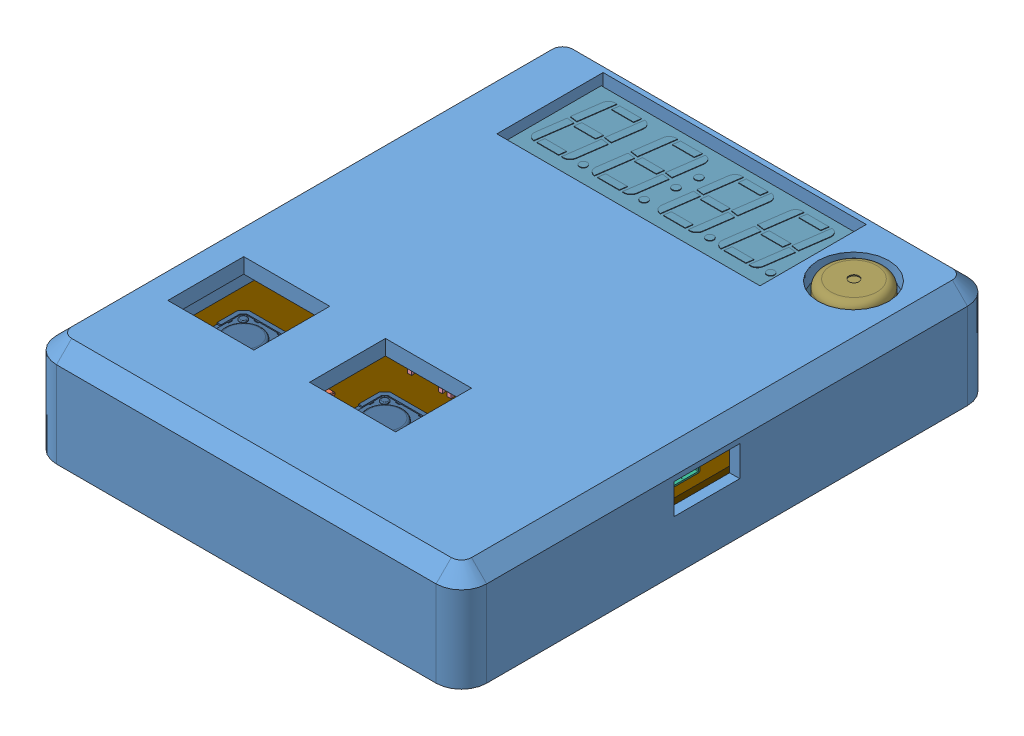
SolidWorks assembly Timer_AssemV1, configuration Default. Lengths in mm.
Overall size (85 20.23 105).
98 component instances, 19 part files, 4 mates.
Components (placement in the parent):
- Timer_EncloserV1-1: Timer_EncloserV1 [Default] at (21.1772 85.8969 138.7154) size (85 17 105)
- DANYS_Kitchen_TimerV3.step-1: DANYS_Kitchen_TimerV3.step [Default] at (-125.543 94.9469 34.9235) x (1 0 0) z (0 1 0) size (78.74 99.06 18.23)
  - R_0805_2012Metric.step-1: R_0805_2012Metric.step [Default] at (146.1142 -79.1758 1.65) x (0 1 0) z (0 0 1) size (2 1.2 0.45)
    - SOLID.step-1: SOLID.step [Default] at origin size (2 1.2 0.45)
  - R_0603_1608Metric.step-1: R_0603_1608Metric.step [Default] at (127 -96.52 1.65) x (0 1 0) z (0 0 1) size (1.6 0.8 0.45)
    - SOLID-0.step-1: SOLID-0.step [Default] at origin size (1.6 0.8 0.45)
  - R_0805_2012Metric.step-2: R_0805_2012Metric.step [Default] at (134.6842 -79.1758 1.65) x (0 1 0) z (0 0 1) size (2 1.2 0.45)
    - SOLID.step-1: SOLID.step [Default] at origin size (2 1.2 0.45)
  - C_0603_1608Metric.step-1: C_0603_1608Metric.step [Default] at (111.635 -90.2 1.65) size (1.6 0.8 0.8)
    - SOLID-1.step-1: SOLID-1.step [Default] at origin size (1.6 0.8 0.8)
  - LED_0805_2012Metric.step-1: LED_0805_2012Metric.step [Default] at (160.845 -95.0025 1.65) x (0 -1 0) z (0 0 1) size (2 1.25 1.1)
    - SOLID-2.step-1: SOLID-2.step [Default] at origin size (2 1.25 1.1)
  - USB_Mini-B_Lumberg_2486_01_Horizontal.step-1: USB_Mini-B_Lumberg_2486_01_Horizontal.step [Default] at (179.07 -107.95 1.65) x (0 1 0) z (0 0 1) size (9.9 9.21 5)
    - SOLID-3.step-1: SOLID-3.step [Default] at origin size (9.9 9.21 5)
  - R_0805_2012Metric.step-3: R_0805_2012Metric.step [Default] at (138.4942 -79.1758 1.65) x (0 1 0) z (0 0 1) size (2 1.2 0.45)
    - SOLID.step-1: SOLID.step [Default] at origin size (2 1.2 0.45)
  - C_0603_1608Metric.step-2: C_0603_1608Metric.step [Default] at (144.0856 -95.1424 1.65) x (0 1 0) z (0 0 1) size (1.6 0.8 0.8)
    - SOLID-1.step-1: SOLID-1.step [Default] at origin size (1.6 0.8 0.8)
  - LED_0805_2012Metric.step-2: LED_0805_2012Metric.step [Default] at (113.03 -63.8325 1.65) x (0 -1 0) z (0 0 1) size (2 1.25 1.1)
    - SOLID-2.step-1: SOLID-2.step [Default] at origin size (2 1.25 1.1)
  - R_0805_2012Metric.step-4: R_0805_2012Metric.step [Default] at (110.49 -68.58 1.65) x (0 1 0) z (0 0 1) size (2 1.2 0.45)
    - SOLID.step-1: SOLID.step [Default] at origin size (2 1.2 0.45)
  - R_0805_2012Metric.step-5: R_0805_2012Metric.step [Default] at (142.3042 -79.1758 1.65) x (0 1 0) z (0 0 1) size (2 1.2 0.45)
    - SOLID.step-1: SOLID.step [Default] at origin size (2 1.2 0.45)
  - R_0603_1608Metric.step-2: R_0603_1608Metric.step [Default] at (149.2111 -95.8706 1.65) size (1.6 0.8 0.45)
    - SOLID-0.step-1: SOLID-0.step [Default] at origin size (1.6 0.8 0.45)
  - C_0603_1608Metric.step-3: C_0603_1608Metric.step [Default] at (140.4888 -95.1249 1.65) x (0 -1 0) z (0 0 1) size (1.6 0.8 0.8)
    - SOLID-1.step-1: SOLID-1.step [Default] at origin size (1.6 0.8 0.8)
  - Crystal_SMD_Abracon_ABM8G-4Pin_3.2x2.5mm.step-1: Crystal_SMD_Abracon_ABM8G-4Pin_3.2x2.5mm.step [Default] at (136.5905 -94.9415 1.65) x (-1 0 0) z (0 0 1) size (3.2 2.5 0.64)
    - SOLID-4.step-1: SOLID-4.step [Default] at origin size (3.2 2.5 0.64)
  - C_0603_1608Metric.step-4: C_0603_1608Metric.step [Default] at (145.6251 -116.0418 1.65) x (0 -1 0) z (0 0 1) size (1.6 0.8 0.8)
    - SOLID-1.step-1: SOLID-1.step [Default] at origin size (1.6 0.8 0.8)
  - R_0805_2012Metric.step-6: R_0805_2012Metric.step [Default] at (134.62 -128.27 1.65) size (2 1.2 0.45)
    - SOLID.step-1: SOLID.step [Default] at origin size (2 1.2 0.45)
  - TSSOP-16_4.4x5mm_P0.65mm.step-1: TSSOP-16_4.4x5mm_P0.65mm.step [Default] at (134.8073 -86.6676 1.65) x (0 -1 0) z (0 0 1) size (6.4 5 1.1)
    - SOLID-5.step-1: SOLID-5.step [Default] at origin size (6.4 5 1.1)
  - C_0603_1608Metric.step-5: C_0603_1608Metric.step [Default] at (115.725 -93.98 1.65) x (-1 0 0) z (0 0 1) size (1.6 0.8 0.8)
    - SOLID-1.step-1: SOLID-1.step [Default] at origin size (1.6 0.8 0.8)
  - C_0603_1608Metric.step-6: C_0603_1608Metric.step [Default] at (152.6468 -106.8933 1.65) size (1.6 0.8 0.8)
    - SOLID-1.step-1: SOLID-1.step [Default] at origin size (1.6 0.8 0.8)
  - LED_0805_2012Metric.step-3: LED_0805_2012Metric.step [Default] at (110.49 -63.8325 1.65) x (0 -1 0) z (0 0 1) size (2 1.25 1.1)
    - SOLID-2.step-1: SOLID-2.step [Default] at origin size (2 1.25 1.1)
  - R_0603_1608Metric.step-3: R_0603_1608Metric.step [Default] at (164.1964 -95.2027 1.65) x (0 -1 0) z (0 0 1) size (1.6 0.8 0.45)
    - SOLID-0.step-1: SOLID-0.step [Default] at origin size (1.6 0.8 0.45)
  - C_0603_1608Metric.step-7: C_0603_1608Metric.step [Default] at (152.6692 -110.0092 1.65) size (1.6 0.8 0.8)
    - SOLID-1.step-1: SOLID-1.step [Default] at origin size (1.6 0.8 0.8)
  - R_0603_1608Metric.step-4: R_0603_1608Metric.step [Default] at (170.625 -107.1515 1.65) x (-1 0 0) z (0 0 1) size (1.6 0.8 0.45)
    - SOLID-0.step-1: SOLID-0.step [Default] at origin size (1.6 0.8 0.45)
  - TQFP-44_10x10mm_P0.8mm.step-1: TQFP-44_10x10mm_P0.8mm.step [Default] at (143.185 -106.68 1.65) x (-1 0 0) z (0 0 1) size (12 12 1.1)
    - SOLID-6.step-1: SOLID-6.step [Default] at origin size (12 12 1.1)
  - C_0603_1608Metric.step-8: C_0603_1608Metric.step [Default] at (111.635 -92.71 1.65) size (1.6 0.8 0.8)
    - SOLID-1.step-1: SOLID-1.step [Default] at origin size (1.6 0.8 0.8)
  - PTS125_SMD_Button.step-1: PTS125_SMD_Button.step [Default] at (120.65 -130.81 1.65) x (0 -1 0) z (-1 0 0) size (12 4.3 15.3)
    - SOLID-8.step-1: SOLID-8.step [Default] at origin size (12 4.3 15.3)
  - C_0603_1608Metric.step-9: C_0603_1608Metric.step [Default] at (138.43 -87.135 1.65) x (0 1 0) z (0 0 1) size (1.6 0.8 0.8)
    - SOLID-1.step-1: SOLID-1.step [Default] at origin size (1.6 0.8 0.8)
  - PinSocket_2x04_P2.54mm_Vertical.step-1: PinSocket_2x04_P2.54mm_Vertical.step [Default] at (123.86 -90.17 1.65) size (5.08 10.16 10.1)
    - SOLID-9.step-1: SOLID-9.step [Default] at origin size (5.08 10.16 10.1)
  - C_0603_1608Metric.step-10: C_0603_1608Metric.step [Default] at (152.6324 -105.2577 1.65) size (1.6 0.8 0.8)
    - SOLID-1.step-1: SOLID-1.step [Default] at origin size (1.6 0.8 0.8)
  - R_0805_2012Metric.step-7: R_0805_2012Metric.step [Default] at (119.4442 -79.1758 1.65) x (0 1 0) z (0 0 1) size (2 1.2 0.45)
    - SOLID.step-1: SOLID.step [Default] at origin size (2 1.2 0.45)
  - Buzzer_12x9.5RM7.6.step-1: Buzzer_12x9.5RM7.6.step [Default] at (172.73 -66.04 1.65) size (12 12 12.53)
    - SOLID-10.step-1: SOLID-10.step [Default] at origin size (12 12 12.53)
  - R_0805_2012Metric.step-8: R_0805_2012Metric.step [Default] at (123.2542 -79.1758 1.65) x (0 1 0) z (0 0 1) size (2 1.2 0.45)
    - SOLID.step-1: SOLID.step [Default] at origin size (2 1.2 0.45)
  - R_0805_2012Metric.step-9: R_0805_2012Metric.step [Default] at (134.62 -133.35 1.65) x (-1 0 0) z (0 0 1) size (2 1.2 0.45)
    - SOLID.step-1: SOLID.step [Default] at origin size (2 1.2 0.45)
  - C_0805_2012Metric.step-1: C_0805_2012Metric.step [Default] at (146.05 -94.93 1.65) x (0 1 0) z (0 0 1) size (2 1.25 1.25)
    - SOLID-11.step-1: SOLID-11.step [Default] at origin size (2 1.25 1.25)
  - CA56-12EWA.step-1: CA56-12EWA.step [Default] at (135.89 -73.66 1.65) x (0 1 0) z (0 0 1) size (19 50.3 12.2)
    - SOLID-12.step-1: SOLID-12.step [Default] at origin size (19 50.3 12.2)
  - SOT-23-6.step-1: SOT-23-6.step [Default] at (163.6975 -107.63 1.65) x (-1 0 0) z (0 0 1) size (2.8 2.9 1.55)
    - SOLID-13.step-1: SOLID-13.step [Default] at origin size (2.8 2.9 1.55)
  - C_0603_1608Metric.step-11: C_0603_1608Metric.step [Default] at (142.3246 -95.1338 1.65) x (0 1 0) z (0 0 1) size (1.6 0.8 0.8)
    - SOLID-1.step-1: SOLID-1.step [Default] at origin size (1.6 0.8 0.8)
  - C_0603_1608Metric.step-12: C_0603_1608Metric.step [Default] at (133.1636 -103.1567 1.65) x (-1 0 0) z (0 0 1) size (1.6 0.8 0.8)
    - SOLID-1.step-1: SOLID-1.step [Default] at origin size (1.6 0.8 0.8)
  - SOT-23-5.step-1: SOT-23-5.step [Default] at (116.215 -91.17 1.65) size (2.8 2.9 1.55)
    - SOLID-14.step-1: SOLID-14.step [Default] at origin size (2.8 2.9 1.55)
  - R_0805_2012Metric.step-10: R_0805_2012Metric.step [Default] at (127.0642 -79.1758 1.65) x (0 1 0) z (0 0 1) size (2 1.2 0.45)
    - SOLID.step-1: SOLID.step [Default] at origin size (2 1.2 0.45)
  - C_0603_1608Metric.step-13: C_0603_1608Metric.step [Default] at (147.3397 -116.0305 1.65) x (0 -1 0) z (0 0 1) size (1.6 0.8 0.8)
    - SOLID-1.step-1: SOLID-1.step [Default] at origin size (1.6 0.8 0.8)
  - R_0805_2012Metric.step-11: R_0805_2012Metric.step [Default] at (130.8742 -79.1758 1.65) x (0 1 0) z (0 0 1) size (2 1.2 0.45)
    - SOLID.step-1: SOLID.step [Default] at origin size (2 1.2 0.45)
  - R_0603_1608Metric.step-5: R_0603_1608Metric.step [Default] at (170.6603 -109.0096 1.65) x (-1 0 0) z (0 0 1) size (1.6 0.8 0.45)
    - SOLID-0.step-1: SOLID-0.step [Default] at origin size (1.6 0.8 0.45)
  - C_0603_1608Metric.step-14: C_0603_1608Metric.step [Default] at (139.4571 -115.9516 1.65) x (0 -1 0) z (0 0 1) size (1.6 0.8 0.8)
    - SOLID-1.step-1: SOLID-1.step [Default] at origin size (1.6 0.8 0.8)
  - R_0805_2012Metric.step-12: R_0805_2012Metric.step [Default] at (113.03 -68.58 1.65) x (0 1 0) z (0 0 1) size (2 1.2 0.45)
    - SOLID.step-1: SOLID.step [Default] at origin size (2 1.2 0.45)
  - PTS125_SMD_Button.step-2: PTS125_SMD_Button.step [Default] at (148.59 -130.81 1.65) x (0 1 0) z (1 0 0) size (12 4.3 15.3)
    - SOLID-8.step-1: SOLID-8.step [Default] at origin size (12 4.3 15.3)
  - PinSocket_2x03_P2.54mm_Vertical.step-1: PinSocket_2x03_P2.54mm_Vertical.step [Default] at (165.1 -100.33 -0.05) x (0 1 0) z (0 0 -1) size (5.08 7.62 10.1)
    - SOLID-7.step-1: SOLID-7.step [Default] at origin size (5.08 7.62 10.1)
  - PCB.step-1: PCB.step [Default] at origin size (78.74 99.06 1.6)
- Timer_Top-1: Timer_Top [Default] at (21.1772 102.8969 138.7154) size (85 3 105)
Mates (geometry in assembly coordinates):
- Coincident2: coincident anti-aligned: plane of Timer_EncloserV1-1 through (21.1772 102.8969 138.7154) normal (0 1 0); plane of Timer_Top-1 through (21.1772 102.8969 138.7154) normal (0 -1 0)
- Coincident4: coincident aligned: line of Timer_EncloserV1-1 through (-21.3228 102.8969 91.2154) axis (0 0 1); line of Timer_Top-1 through (-21.3228 102.8969 91.2154) axis (0 0 1)
- Coincident5: coincident aligned: line of Timer_EncloserV1-1 through (-16.3228 102.8969 191.2154) axis (1 0 0); line of Timer_Top-1 through (-16.3228 102.8969 191.2154) axis (1 0 0)
- Coincident6: coincident anti-aligned: plane of Timer_EncloserV1-1 through (21.1772 87.8969 138.7154) normal (0 1 0); plane of DANYS_Kitchen_TimerV3.step-1/PinSocket_2x03_P2.54mm_Vertical.step-1/SOLID-7.step-1 through (33.207 87.8969 133.9835) normal (0 -1 0)
